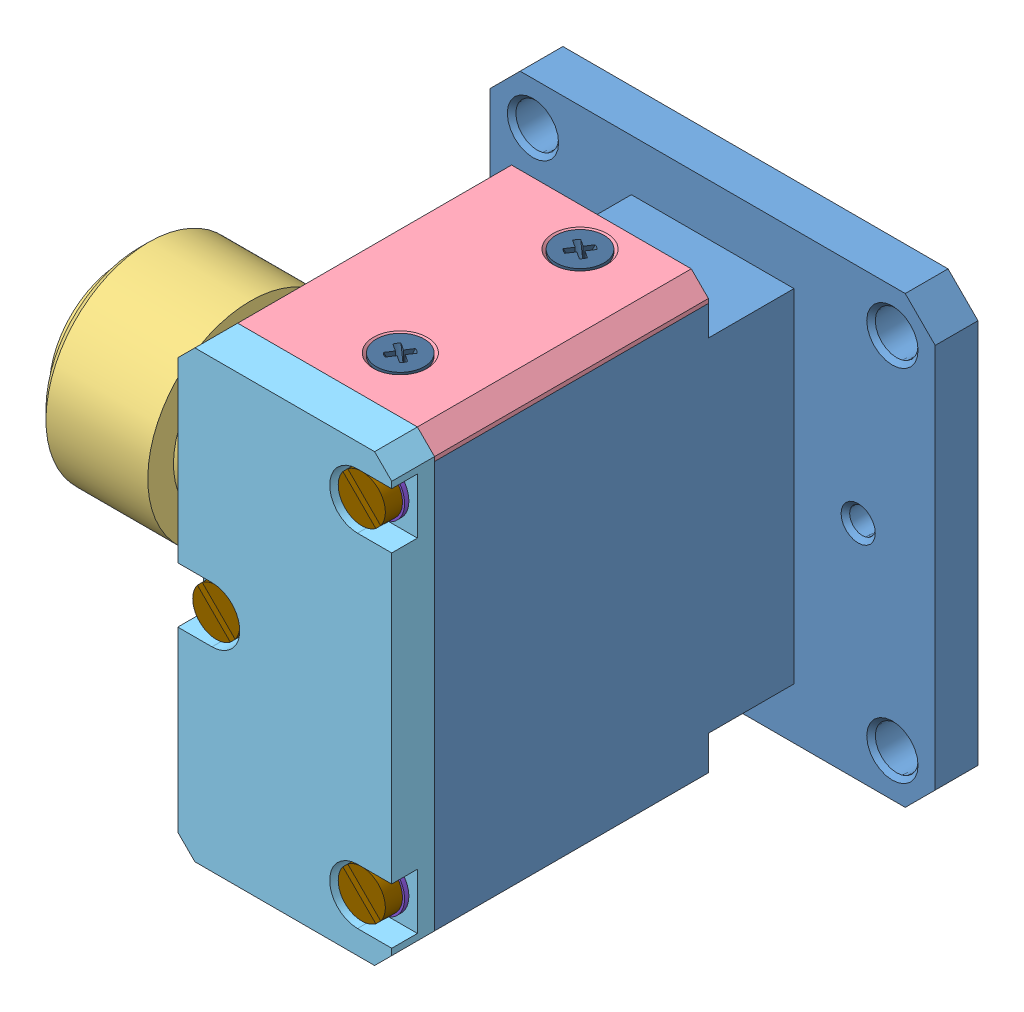
SolidWorks assembly sborka, configuration По умолчанию. Lengths in mm.
Overall size (70 52 52).
23 component instances, 10 part files, 36 mates.
Components (placement in the parent):
- Корпус-1: Корпус [По умолчанию] at origin size (52 52 47)
- Делитель-1: Делитель [По умолчанию] at (-1 -17.5 30) x (0 1 0) z (0 0 1) size (41 45.5 7)
- Разъём-1: Разъём [По умолчанию] at (-17.5 0 30) x (0 1 0) z (1 0 0) size (30 25 36.5)
- Крышка боковая-2: Крышка боковая [По умолчанию] at (-3 26 31) x (0 -1 0) z (-1 0 0) size (4 32 25)
- Крышка-2: Крышка [По умолчанию] at (-3 0 47) x (0 -1 0) z (0 0 1) size (52 25 10)
- Втулка-1: Втулка [По умолчанию] at (-1 21.5 30) x (-0.928817 0 -0.370539) z (0 -1 0) size (12 12 4)
- Винт М2.5-1: Винт М2.5 [По умолчанию] at (-1 -19 30) x (-0.707107 0 0.707107) z (0 -1 0) size (6.2 6.2 18.7)
- ГОСТ 10450-78-1: ГОСТ 10450-78 [Шайба A.3 ГОСТ 10450-78] at (-18 -11 39) x (0 0 -1) z (-1 0 0) size (6 6 0.5)
- ГОСТ 1491-80-5: ГОСТ 1491-80 [Винт A.M3х6 ГОСТ 1491-80] at (-20 -11 39) x (0 0.707107 -0.707107) z (-1 0 0) size (5.5 5.5 8)
- ГОСТ 10450-78-2: ГОСТ 10450-78 [Шайба A.3 ГОСТ 10450-78] at (-18 -11 21) x (0 0 -1) z (-1 0 0) size (6 6 0.5)
- ГОСТ 10450-78-3: ГОСТ 10450-78 [Шайба A.3 ГОСТ 10450-78] at (-18 11 39) x (0 0 -1) z (-1 0 0) size (6 6 0.5)
- ГОСТ 10450-78-4: ГОСТ 10450-78 [Шайба A.3 ГОСТ 10450-78] at (-18 11 21) x (0 0 -1) z (-1 0 0) size (6 6 0.5)
- ГОСТ 1491-80-6: ГОСТ 1491-80 [Винт A.M3х6 ГОСТ 1491-80] at (-20 -11 21) x (0 0.707107 -0.707107) z (-1 0 0) size (5.5 5.5 8)
- ГОСТ 1491-80-7: ГОСТ 1491-80 [Винт A.M3х6 ГОСТ 1491-80] at (-20 11 39) x (0 0.707107 -0.707107) z (-1 0 0) size (5.5 5.5 8)
- ГОСТ 1491-80-8: ГОСТ 1491-80 [Винт A.M3х6 ГОСТ 1491-80] at (-20 11 21) x (0 0.707107 -0.707107) z (-1 0 0) size (5.5 5.5 8)
- ГОСТ 1491-80-10: ГОСТ 1491-80 [Винт A.M3х6 ГОСТ 1491-80] at (-11.5 0 51.5) x (-0.707107 -0.707107 0) z (0 0 1) size (5.5 5.5 8)
- ГОСТ 10450-78-5: ГОСТ 10450-78 [Шайба A.3 ГОСТ 10450-78] at (-11.5 0 49.5) x (-0.923728 -0.383049 0) z (0 0 1) size (6 6 0.5)
- ГОСТ 1491-80-14: ГОСТ 1491-80 [Винт A.M3х6 ГОСТ 1491-80] at (5.5 20 51.5) x (-0.707107 -0.707107 0) z (0 0 1) size (5.5 5.5 8)
- ГОСТ 1491-80-15: ГОСТ 1491-80 [Винт A.M3х6 ГОСТ 1491-80] at (5.5 -20 51.5) x (-0.707107 -0.707107 0) z (0 0 1) size (5.5 5.5 8)
- ГОСТ 10450-78-9: ГОСТ 10450-78 [Шайба A.3 ГОСТ 10450-78] at (5.5 20 49.5) x (-0.923728 -0.383049 0) z (0 0 1) size (6 6 0.5)
- ГОСТ 10450-78-10: ГОСТ 10450-78 [Шайба A.3 ГОСТ 10450-78] at (5.5 -20 49.5) x (-0.923728 -0.383049 0) z (0 0 1) size (6 6 0.5)
- ГОСТ 17475-80-3: ГОСТ 17475-80 [Винт A2.M3x6 ГОСТ 17475-80] at (-1 26 19.5) x (-0.837169 0 -0.546944) z (0 1 0) size (5.6 5.6 6)
- ГОСТ 17475-80-4: ГОСТ 17475-80 [Винт A2.M3x6 ГОСТ 17475-80] at (-1 26 40.5) x (-0.837169 0 -0.546944) z (0 1 0) size (5.6 5.6 6)
Mates (geometry in assembly coordinates):
- Концентричный3: concentric anti-aligned: cylinder of Корпус-1 through (26.001 0 30) axis (-1 0 0) radius 9; cylinder of Делитель-1 through (-43 0 30) axis (1 0 0) radius 2.75
- Концентричный4: concentric anti-aligned: cylinder of Корпус-1 through (-1 20.5 30) axis (0 1 0) radius 6; cylinder of Делитель-1 through (-1 17.5 30) axis (0 -1 0) radius 2.75
- Концентричный6: concentric anti-aligned: cylinder of Делитель-1 through (-43 0 30) axis (1 0 0) radius 2.75; cylinder of Разъём-1 through (-30 0 30) axis (-1 0 0) radius 7
- Концентричный7: concentric aligned: cylinder of Корпус-1 through (-15.5 -11 39) axis (-1 0 0) radius 1.25; cylinder of Разъём-1 through (-15.5 -11 39) axis (-1 0 0) radius 1.55
- Совпадение3: coincident anti-aligned: plane of Корпус-1 through (-15.5 -26 15) normal (-1 0 0); plane of Разъём-1 through (-15.5 0 30) normal (1 0 0)
- Концентричный11: concentric aligned: cylinder of Корпус-1 through (5.5 20 47) axis (0 0 1) radius 1.25; cylinder of Крышка-2 through (5.5 20 42) axis (0 0 1) radius 1.6
- Концентричный12: concentric aligned: cylinder of Корпус-1 through (-11.5 0 47) axis (0 0 1) radius 1.25; cylinder of Крышка-2 through (-11.5 0 42) axis (0 0 1) radius 1.6
- Совпадение7: coincident anti-aligned: plane of Корпус-1 through (0 0 47) normal (0 0 1); plane of Крышка-2 through (-3 0 47) normal (0 0 -1)
- Концентричный15: concentric aligned: cylinder of Корпус-1 through (-1 23.5 19.5) axis (0 1 0) radius 1.25; cylinder of Крышка боковая-2 through (-1 26 19.5) axis (0 1 0) radius 1.7
- Концентричный16: concentric aligned: cylinder of Корпус-1 through (-1 23.5 40.5) axis (0 1 0) radius 1.25; cylinder of Крышка боковая-2 through (-1 26 40.5) axis (0 1 0) radius 1.7
- Совпадение8: coincident anti-aligned: plane of Корпус-1 through (0 23.5 0) normal (0 1 0); plane of Крышка боковая-2 through (-3 23.5 31) normal (0 -1 0)
- Концентричный17: concentric aligned: cylinder of Корпус-1 through (-1 -26.001 30) axis (0 1 0) radius 5; cylinder of Втулка-1 through (-1 17.5 30) axis (0 1 0) radius 5
- Совпадение9: coincident aligned: plane of Корпус-1 through (-7.5 17.5 0) normal (0 -1 0); plane of Втулка-1 through (-1 17.5 30) normal (0 -1 0)
- Концентричный18: concentric aligned: cylinder of Делитель-1 through (-1 -10.5 30) axis (0 -1 0) radius 2; cylinder of Винт М2.5-1 through (-1 -12 30) axis (0 -1 0) radius 2
- Совпадение10: coincident anti-aligned: plane of Корпус-1 through (-1 -19 30) normal (0 -1 0); plane of Винт М2.5-1 through (-1 -19 30) normal (0 1 0)
- Угол2: planar angle = 0.785398 rad aligned: plane of Винт М2.5-1 through (1.8638 -23.5 32.086) normal (-0.707107 0 0.707107); plane of Корпус-1 through (0 0 5) normal (0 0 1)
- Концентричный19: concentric aligned: cylinder of Крышка-2 through (5.5 -20 42) axis (0 0 1) radius 1.6; cylinder of ГОСТ 1491-80-2 through (5.5 -20 51) axis (0 0 1) radius 1.5
- Совпадение13: coincident anti-aligned: plane of Крышка-2 through (-3 0 49) normal (0 0 1); plane of ГОСТ 1491-80-2 through (5.5 -17.25 49) normal (0 0 -1)
- Концентричный20: concentric aligned: cylinder of Крышка-2 through (5.5 20 42) axis (0 0 1) radius 1.6; cylinder of ГОСТ 1491-80-3 through (5.5 20 51) axis (0 0 1) radius 1.5
- Совпадение14: coincident anti-aligned: plane of Крышка-2 through (-3 0 49) normal (0 0 1); plane of ГОСТ 1491-80-3 through (5.5 22.75 49) normal (0 0 -1)
- Концентричный21: concentric aligned: cylinder of Крышка-2 through (-11.5 0 42) axis (0 0 1) radius 1.6; cylinder of ГОСТ 1491-80-4 through (-11.5 0 51) axis (0 0 1) radius 1.5
- Совпадение15: coincident anti-aligned: plane of Крышка-2 through (-3 0 49) normal (0 0 1); plane of ГОСТ 1491-80-4 through (-11.5 2.75 49) normal (0 0 -1)
- Концентричный22: concentric aligned: cylinder of ГОСТ 1491-80-5 through (-20 -11 39) axis (-1 0 0) radius 1.5; cylinder of ГОСТ 10450-78-1 through (-17.5 -11 39) axis (-1 0 0) radius 3
- Совпадение16: coincident anti-aligned: plane of ГОСТ 10450-78-1 through (-18 -11 39) normal (-1 0 0); plane of ГОСТ 1491-80-5 through (-18 -12.9445 37.0555) normal (1 0 0)
- Концентричный23: concentric aligned: cylinder of Корпус-1 through (-15.5 -11 39) axis (-1 0 0) radius 1.25; cylinder of ГОСТ 1491-80-5 through (-20 -11 39) axis (-1 0 0) radius 1.5
- Совпадение17: coincident anti-aligned: plane of Разъём-1 through (-17.5 0 30) normal (-1 0 0); plane of ГОСТ 10450-78-1 through (-17.5 -11 39) normal (1 0 0)
- Угол3: planar angle = 0.785398 rad aligned: plane of ГОСТ 1491-80-5 through (-19.1 -8.7726 40.6617) normal (0 -0.707107 0.707107); plane of Разъём-1 through (-15.5 -15 42.5) normal (0 0 1)
- Концентричный24: concentric aligned: cylinder of ГОСТ 1491-80-10 through (-11.5 0 51.5) axis (0 0 1) radius 1.5; cylinder of ГОСТ 10450-78-5 through (-11.5 0 49) axis (0 0 1) radius 1.6
- Совпадение19: coincident anti-aligned: plane of ГОСТ 1491-80-10 through (-9.5555 -1.9445 49.5) normal (0 0 -1); plane of ГОСТ 10450-78-5 through (-11.5 0 49.5) normal (0 0 1)
- Концентричный25: concentric aligned: cylinder of Крышка-2 through (-11.5 0 42) axis (0 0 1) radius 1.6; cylinder of ГОСТ 1491-80-10 through (-11.5 0 51.5) axis (0 0 1) radius 1.5
- Совпадение20: coincident anti-aligned: plane of Крышка-2 through (-3 0 49) normal (0 0 1); plane of ГОСТ 10450-78-5 through (-11.5 0 49) normal (0 0 -1)
- Угол4: planar angle = 0.785398 rad aligned: plane of ГОСТ 1491-80-10 through (-13.1617 2.2274 50.6) normal (-0.707107 -0.707107 0); plane of Крышка-2 through (-15.5 26 52) normal (-1 0 0)
- Концентричный26: concentric aligned: cylinder of Корпус-1 through (-1 23.5 19.5) axis (0 1 0) radius 1.25; cylinder of ГОСТ 17475-80-1 through (-1 26 19.5) axis (0 1 0) radius 1.5
- Совпадение24: coincident aligned: cone of Крышка боковая-2 through (-1 26 19.5) axis (0 -1 0); cone of ГОСТ 17475-80-1 through (-1 24.35 19.5) axis (0 -1 0)
- Концентричный27: concentric aligned: cylinder of Корпус-1 through (-1 23.5 19.5) axis (0 1 0) radius 1.25; cylinder of ГОСТ 17475-80-3 through (-1 26 19.5) axis (0 1 0) radius 1.5
- Совпадение25: coincident aligned: cone of Крышка боковая-2 through (-1 26 19.5) axis (0 -1 0); cone of ГОСТ 17475-80-3 through (-1 24.35 19.5) axis (0 -1 0)
